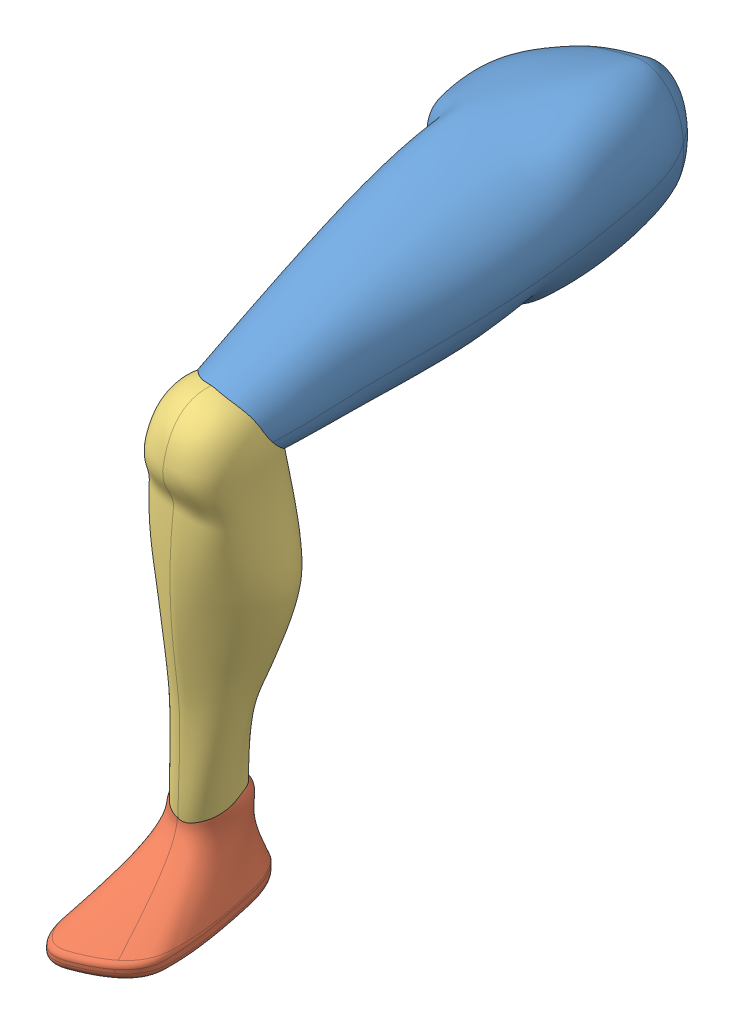
SolidWorks assembly together, configuration 默认. Lengths in mm.
Overall size (200.41 805.87 722.27).
3 component instances, 3 part files, 3 mates.
Components (placement in the parent):
- LEF THIGH-1: LEF THIGH [默认] at (-100 181.2042 -18.7153) size (200.41 302.51 588.66)
- LEFT FEET-1: LEFT FEET [默认] at (-100 430.2673 437.2953) x (1 0 0) z (0 -0.935261 0.353959) size (101.22 216.1 181.75)
- LEFT LEG-1: LEFT LEG [默认] at (-101.7255 402.9828 596.0984) x (1 0 0) z (0 -0.983726 0.179673) size (117.3 169.24 460.42)
Mates (geometry in assembly coordinates):
- 重合9: coordinate: point of LEF THIGH-1; point of assembly
- 重合10: coincident aligned: circle of LEF THIGH-1; circle of LEFT LEG-1
- 重合11: coincident aligned: circle of LEFT FEET-1; circle of LEFT LEG-1
